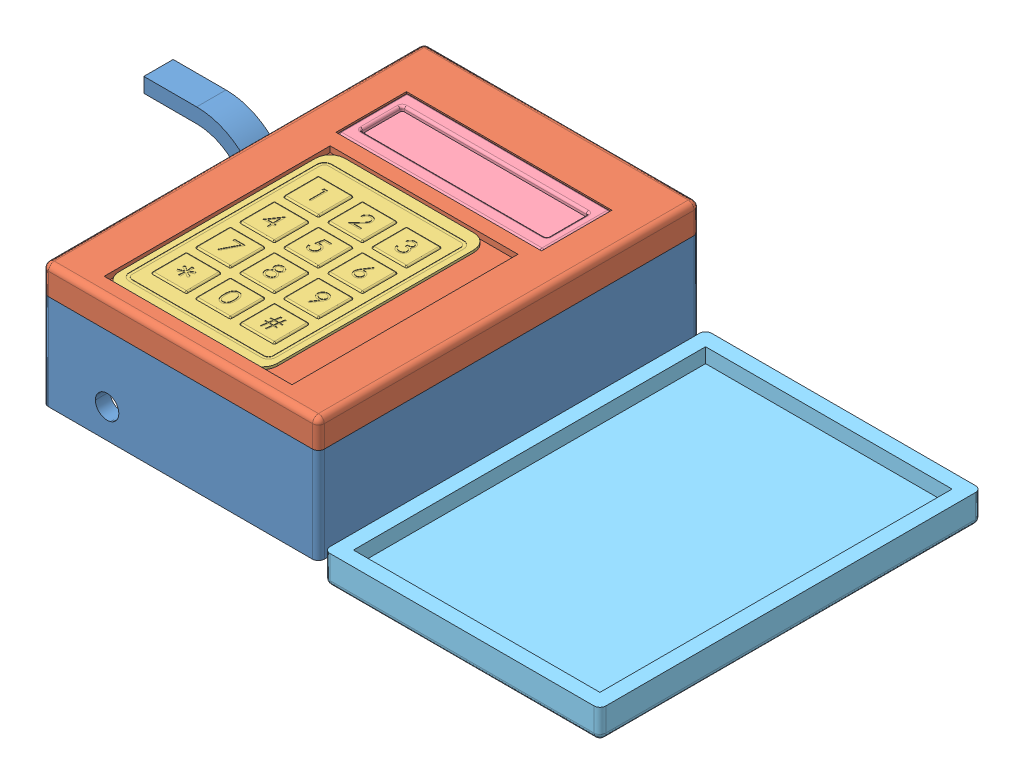
SolidWorks assembly enclosure assembly, configuration Default. Lengths in mm.
Overall size (230.43 48.25 130).
5 component instances, 5 part files, 11 mates.
Components (placement in the parent):
- middle_from_step-1: middle_from_step [Default] at (3.5104 44.7564 185.0037) size (134.5 45 130)
- UPPER__FROM_STEP-1: UPPER__FROM_STEP [Default] at (3.5104 79.7564 185.0037) size (94 9.5 130)
- keypad-1: keypad [Default] at (45.5104 84.7564 140.5037) x (1 0 0) z (0 1 0) size (54 77 1.31)
- LCDScreen-1: LCDScreen [Default] at (50.5854 77.2314 84.9099) size (79.38 18.26 34.92)
- Part1^enclosure assembly-1: Part1^enclosure assembly [Default] at (-1.8662 44.4384 183.8923) x (-1 0 0) z (0 -1 0) size (94 130 10) (virtual)
Mates (geometry in assembly coordinates):
- Coincident1: coincident: plane of middle_from_step-1 through (5.5104 77.2564 183.0037) normal (0 1 0); plane of UPPER__FROM_STEP-1 through (3.5104 77.2564 185.0037) normal (0 -1 0)
- Coincident3: coincident: plane of middle_from_step-1 through (3.5104 79.7564 185.0037) normal (0 0 1); plane of UPPER__FROM_STEP-1 through (3.5104 77.2564 185.0037) normal (0 0 1)
- Coincident4: coincident: plane of middle_from_step-1 through (3.5104 79.7564 185.0037) normal (-1 0 0); plane of UPPER__FROM_STEP-1 through (3.5104 77.2564 55.0037) normal (-1 0 0)
- Coincident5: coincident: plane of UPPER__FROM_STEP-1 through (3.5104 84.7564 185.0037) normal (0 1 0); plane of keypad-1 through (45.5104 84.7564 140.5037) normal (0 -1 0)
- Coincident6: coincident: plane of UPPER__FROM_STEP-1 through (3.5104 86.7564 185.0037) normal (0 1 0); plane of LCDScreen-1 through (50.5854 86.7564 84.9099) normal (0 1 0)
- Coincident11: coincident: plane of UPPER__FROM_STEP-1 through (15.5104 86.7564 73.0037) normal (0 0 1); plane of LCDScreen-1 through (50.5854 86.7564 73.0037) normal (0 0 -1)
- Coincident12: coincident: plane of UPPER__FROM_STEP-1 through (85.5104 86.7564 73.0037) normal (-1 0 0); plane of LCDScreen-1 through (85.5104 86.7564 84.9099) normal (1 0 0)
- Coincident15: coincident: plane of UPPER__FROM_STEP-1 through (82.5104 84.7564 102.0037) normal (0 0 1); plane of keypad-1 through (18.5104 85.5664 102.0037) normal (0 0 -1)
- Coincident16: coincident: plane of UPPER__FROM_STEP-1 through (18.5104 84.7564 102.0037) normal (1 0 0); plane of keypad-1 through (18.5104 85.5664 102.0037) normal (-1 0 0)
- Parallel1: parallel: plane of middle_from_step-1 through (3.5104 44.7564 185.0037) normal (0 -1 0); plane of Part1^enclosure assembly-1 through (-1.8662 44.4384 183.8923) normal (0 1 0)
- Coincident21: coincident: plane of middle_from_step-1 through (3.5104 79.7564 185.0037) normal (0 0 1); plane of Part1^enclosure assembly-1 through (193.438 39.4384 185.0037) normal (0 0 1)
